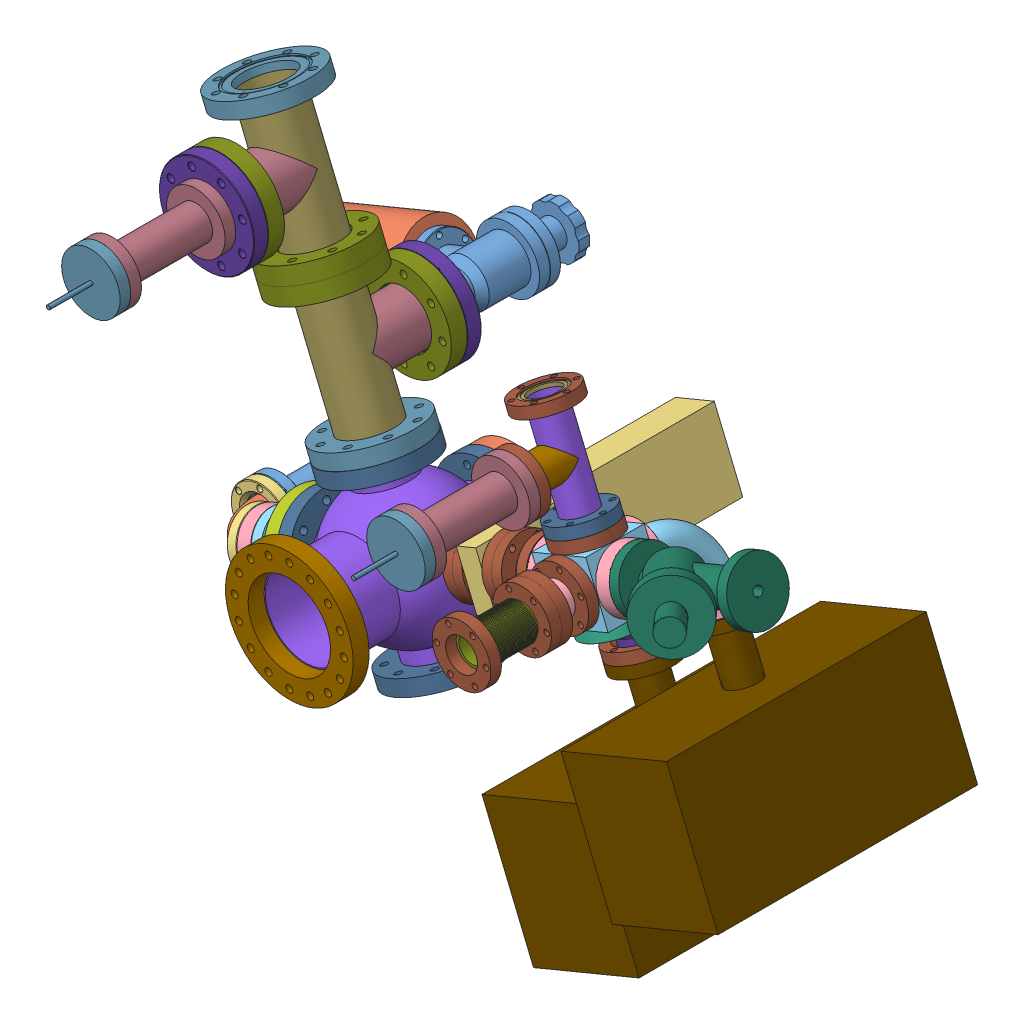
SolidWorks assembly Oven_BEC5_v3, configuration Default. Lengths in mm.
Overall size (747.25 839.97 656.21).
101 component instances, 42 part files, 80 mates.
Components (placement in the parent):
- mdc 275 halfnipple-1: mdc 275 halfnipple [Default] at (-24.8274 -18.3346 25.5574) size (69.34 69.34 62.48)
- L275-403502-6: L275-403502 [Default] at (27.1869 1.5159 24.2874) x (-0.923728 -0.383049 0) z (0 0 -1) size (77.27 39.99 77.27)
- 915002-3: 915002 [Default] at (-24.8274 -18.3346 38.2574) x (0 0 -1) z (1 0 0) size (12.7 69.34 69.34)
- mdc 2.75 doublesided_hole-1: mdc 2.75 doublesided_hole [Default] at (43.4775 8.648 79.5644) x (0.146727 -0.353833 -0.923728) z (0.923728 0.383049 0) size (69.34 69.34 19.05)
- 915002-4: 915002 [Default] at (14.1491 -3.5138 79.5644) x (0.923728 0.383049 0) z (0 0 1) size (12.7 69.34 69.34)
- 100014 (2.75 X 1.5 REC)-1: 100014 (2.75 X 1.5 REC) [Default] at (43.4775 8.648 79.5644) x (0.923728 0.383049 0) z (0 0 1) size (12.7 69.34 69.34)
- red1-402032-001-1: red1-402032-001 [Default] at (97.817 31.1814 79.5644) x (-0.923728 -0.383049 0) z (0 0 1) size (60.1 63.5 63.5)
- 110021 (4.5 X 2.5 NR)-1: 110021 (4.5 X 2.5 NR) [Default] at (97.817 31.1814 79.5644) x (-0.923728 -0.383049 0) z (0 0 1) size (17.27 113.54 113.54)
- custom_sixway_cross-1: custom_sixway_cross [Default] at (189.7246 79.077 65.1716) x (-0.923728 -0.383049 0) z (-0.383049 0.923728 0) size (201.17 247.4 209.3)
  - custom_sixway_tube-1: custom_sixway_tube [Default] at (-1.4041 14.3928 -9.0374) size (170.94 210.82 174.24)
  - 6in_CF_flange-3: 6in_CF_flange [Default] at (-1.4041 157.1408 -9.0374) x (1 0 0) z (0 -1 0) size (152.4 152.4 19.05)
  - 4.5in_CF_flange-1: 4.5in_CF_flange [Default] at (85.7179 14.3928 -9.0374) x (0 -1 0) z (0 0 1) size (114.3 17.53 114.3)
  - 4.5in_CF_flange-2: 4.5in_CF_flange [Default] at (-1.4041 14.3928 78.0846) x (1 0 0) z (0 -1 0) size (114.3 17.53 114.3)
  - 4.5in_CF_flange-3: 4.5in_CF_flange [Default] at (-1.4041 14.3928 -113.6854) x (1 0 0) z (0 -1 0) size (114.3 17.53 114.3)
  - 2.75in_CF_flange-1: 2.75in_CF_flange [Default] at (-97.9241 14.3928 -9.0374) x (0 -1 0) z (0 0 1) size (69.85 12.7 69.85)
  - 4.5in_CF_flange-4: 4.5in_CF_flange [Default] at (-1.4041 -90.2552 -9.0374) size (114.3 17.53 114.3)
- T4-404038-2: T4-404038 [Default] at (85.0757 335.1047 79.5644) x (-0.923728 -0.383049 0) z (-0.383049 0.923728 0) size (113.54 142.49 171.45)
  - 404038-001-1: 404038-001 [Default] at origin size (63.51 63.51 152.4)
  - 404038-002-1: 404038-002 [Default] at (0 0 76.2) x (1 0 0) z (0 1 0) size (63.5 63.5 78.71)
  - 110021 (4.5 X 2.5 NR)_1-1: 110021 (4.5 X 2.5 NR)_1 [Default] at (0 0 161.925) x (0 0 -1) z (1 0 0) size (17.27 113.54 113.54)
  - 100021 (4.5 X 2.5 R)_1-1: 100021 (4.5 X 2.5 R)_1 [Default] at (0 73.025 76.2) x (0 1 0) z (0 0 1) size (19.05 113.54 113.54)
    - 100021 (4.5 X 2.5 INS)_1-1: 100021 (4.5 X 2.5 INS)_1 [Default] at origin size (12.04 82.3 82.3)
    - 100021 (4.5 X 2.5 REC)_1-1: 100021 (4.5 X 2.5 REC)_1 [Default] at (-6.35 0 0) x (1 0 0) z (0 0 -1) size (19.05 113.54 113.54)
  - 100021 (4.5 X 2.5 R)_1-2: 100021 (4.5 X 2.5 R)_1 [Default] at (0 0 3.175) x (0 0 -1) z (1 0 0) size (19.05 113.54 113.54)
    - 100021 (4.5 X 2.5 INS)_1-1: 100021 (4.5 X 2.5 INS)_1 [Default] at origin size (12.04 82.3 82.3)
    - 100021 (4.5 X 2.5 REC)_1-1: 100021 (4.5 X 2.5 REC)_1 [Default] at (-6.35 0 0) x (1 0 0) z (0 0 -1) size (19.05 113.54 113.54)
- zerolength 2.75 to 4.5 mdc-3: zerolength 2.75 to 4.5 mdc [Default] at (55.8874 405.4928 165.2894) x (-0.923728 -0.383049 0) z (0 0 -1) size (113.54 113.54 17.27)
- L4-403004_1-3: L4-403004_1 [Default] at (231.0174 -16.8357 -129.9856) x (0 0 1) z (-0.923728 -0.383049 0) size (161.67 161.67 113.54)
  - 403004-001_1-1: 403004-001_1 [Default] at origin size (128.92 128.92 67.08)
  - 100021 (4.5 X 2.5 R)_2-1: 100021 (4.5 X 2.5 R)_2 [Default] at (92.202 95.377 0) x (1 0 0) z (0 0 -1) size (19.05 113.54 113.54)
    - 100021 (4.5 X 2.5 INS)_2-1: 100021 (4.5 X 2.5 INS)_2 [Default] at origin size (12.04 82.3 82.3)
    - 100021 (4.5 X 2.5 REC)_2-1: 100021 (4.5 X 2.5 REC)_2 [Default] at (-6.35 0 0) x (1 0 0) z (0 0 -1) size (19.05 113.54 113.54)
  - 100021 (4.5 X 2.5 R)_2-2: 100021 (4.5 X 2.5 R)_2 [Default] at (0 3.175 0) x (0 -1 0) z (0 0 -1) size (19.05 113.54 113.54)
    - 100021 (4.5 X 2.5 INS)_2-1: 100021 (4.5 X 2.5 INS)_2 [Default] at origin size (12.04 82.3 82.3)
    - 100021 (4.5 X 2.5 REC)_2-1: 100021 (4.5 X 2.5 REC)_2 [Default] at (-6.35 0 0) x (1 0 0) z (0 0 -1) size (19.05 113.54 113.54)
- gatevalve-1: gatevalve [Default] at (298.9549 11.514 55.3656) x (0.383049 -0.923728 0) z (0.923728 0.383049 0) size (88.9 280.54 50.84)
  - gatevalve_body-1: gatevalve_body [Default] at (-95.213 2.8522 48.3049) size (88.9 277.88 50.04)
  - 2.75in_CF_flange-3: 2.75in_CF_flange [Default] at (-95.213 -24.1988 73.7492) x (1 0 0) z (0 1 0) size (69.85 12.7 69.85)
  - 2.75in_CF_flange-4: 2.75in_CF_flange [Default] at (-95.213 -24.1988 35.6049) x (-1 0 0) z (0 -1 0) size (69.85 12.7 69.85)
- minilength_nipple-1: minilength_nipple [Default] at (349.6703 127.2966 78.7528) x (0.383049 -0.923728 0) z (0 0 1) size (69.85 44.45 69.85)
  - minilength_nipple_tube-1: minilength_nipple_tube [Default] at (-7.6879 4.7765 0.8117) size (38.1 19.05 38.1)
  - 2.75in_CF_flange-3: 2.75in_CF_flange [Default] at (-7.6879 14.3015 0.8117) size (69.85 12.7 69.85)
  - 2.75in_CF_flange-4: 2.75in_CF_flange [Default] at (-7.6879 -17.4485 0.8117) size (69.85 12.7 69.85)
- mdc 2.75 doublesided_hole-4: mdc 2.75 doublesided_hole [Default] at (371.6676 144.741 79.5644) x (0.146727 -0.353833 0.923728) z (-0.923728 -0.383049 0) size (69.34 69.34 19.05)
- mdc 2.75 doublesided_hole-5: mdc 2.75 doublesided_hole [Default] at (453.787 178.7941 79.5644) x (0.146727 -0.353833 0.923728) z (-0.923728 -0.383049 0) size (69.34 69.34 19.05)
- six way cube-1: six way cube [Default] at (421.5258 165.4161 79.5644) x (0 0 1) z (-0.923728 -0.383049 0) size (69.85 69.85 69.85)
- 2.75in  window mdc-1: 2.75in  window mdc [Default] at (439.7685 121.4235 79.5644) x (0.853273 0.353833 0.383049) z (-0.383049 0.923728 0) size (69.34 69.34 12.7)
  - Part3^2.75in  window mdc-1: Part3^2.75in  window mdc [Default] at origin size (69.34 69.34 12.7) (virtual)
  - Part4^2.75in  window mdc-1: Part4^2.75in  window mdc [Default] at (0 0 12.7) size (38.1 38.1 2.67) (virtual)
- T275-404002_a-1: T275-404002_a [Default] at (357.4671 319.8944 79.5644) x (0.923728 0.383049 0) z (0.383049 -0.923728 0) size (69.34 97.13 124.92)
  - 404002-001-1: 404002-001 [Default] at origin size (38.1 38.1 114.3)
  - 404002-002-1: 404002-002 [Default] at (0 0 57.15) x (-1 0 0) z (0 1 0) size (38.1 38.1 58.53)
  - 110014 (2.75 X 1.5 NR)_1-1: 110014 (2.75 X 1.5 NR)_1 [Default] at (0 0 113.2586) x (0 0 1) z (-1 0 0) size (12.7 69.34 69.34)
  - 100014 (2.75 X 1.5 R)-1: 100014 (2.75 X 1.5 R) [Default] at (0 62.4586 57.15) x (0 -1 0) z (1 0 0) size (12.7 69.34 69.34)
    - 100014 (2.75 X 1.5 REC)_1-1: 100014 (2.75 X 1.5 REC)_1 [Default] at origin size (12.7 69.34 69.34)
    - 100014 (2.75 X 1.5 INS)-1: 100014 (2.75 X 1.5 INS) [Default] at (1.17 0 0) x (1 0 0) z (0 0.994423 -0.105464) size (6.96 48.1 48.1)
  - 100014 (2.75 X 1.5 R)-2: 100014 (2.75 X 1.5 R) [Default] at (0 0 -5.3086) x (0 0 1) z (-1 0 0) size (12.7 69.34 69.34)
    - 100014 (2.75 X 1.5 REC)_1-1: 100014 (2.75 X 1.5 REC)_1 [Default] at origin size (12.7 69.34 69.34)
    - 100014 (2.75 X 1.5 INS)-1: 100014 (2.75 X 1.5 INS) [Default] at (1.17 0 0) x (1 0 0) z (0 0.994423 -0.105464) size (6.96 48.1 48.1)
- 2.75in_CF_flange-1: 2.75in_CF_flange [Default] at (403.2831 209.4086 79.5644) x (-0.923728 -0.383049 0) z (0 0 1) size (69.85 12.7 69.85)
- nipple 2.75 mdc-2: nipple 2.75 mdc [Default] at (379.3584 267.1034 142.023) x (1 0 0) z (0 -1 0) size (69.85 125.22 69.85)
- ion gauge uhv 24p footprint-2: ion gauge uhv 24p footprint [Default] at (379.3584 267.1034 279.945) x (1 0 0) z (0 1 0) size (69.85 147.62 69.85)
- valve mdc inline all metal small-1: valve mdc inline all metal small [Default] at (470.2109 185.6047 79.5644) x (-0.383049 0.923728 0) z (0 0 -1) size (75.44 172.37 161.4)
- minilength_nipple-2: minilength_nipple [Default] at (429.2137 166.2277 131.9379) x (1 0 0) z (0 -1 0) size (69.85 44.45 69.85)
  - minilength_nipple_tube-1: minilength_nipple_tube [Default] at (-7.6879 4.7765 0.8117) size (38.1 19.05 38.1)
  - 2.75in_CF_flange-3: 2.75in_CF_flange [Default] at (-7.6879 14.3015 0.8117) size (69.85 12.7 69.85)
  - 2.75in_CF_flange-4: 2.75in_CF_flange [Default] at (-7.6879 -17.4485 0.8117) size (69.85 12.7 69.85)
- Bellow_2.75in_CF-1: Bellow_2.75in_CF [Default] at (449.3378 155.3944 206.3015) x (1 0 0) z (0 1 0) size (96.68 84.96 96.68)
  - 2.75in_bellow_tube-1: 2.75in_bellow_tube [Default] at (-27.8121 6.8508 10.0217) size (43.18 63.5 43.18)
  - 2.75in_CF_flange-1: 2.75in_CF_flange [Default] at (-27.8121 47.3621 10.0217) x (-0.837169 0 -0.546944) z (-0.546944 0 0.837169) size (69.85 12.7 69.85)
  - 2.75in_CF_flange-2: 2.75in_CF_flange [Default] at (-27.8121 -24.8992 10.0217) x (-0.837169 0 -0.546944) z (-0.546944 0 0.837169) size (69.85 12.7 69.85)
- 404002-001_1-1: 404002-001_1 [Default] at (115.1337 -161.6135 43.2434)
- 402032-2: 402032 [Default] at (238.3145 -34.4327 -129.9856) x (0.383049 -0.923728 0) z (0 0 1) size (74.93 113.54 113.54)
  - 402032-001-1: 402032-001 [Default] at origin size (60.1 63.5 63.5)
  - 110021 (4.5 X 2.5 NR)-1: 110021 (4.5 X 2.5 NR) [Default] at (-9.525 0 0) size (17.27 113.54 113.54)
  - 100014 (2.75 X 1.5 R)-1: 100014 (2.75 X 1.5 R) [Default] at (65.405 0 0) x (-1 0 0) z (0 0 -1) size (12.7 69.34 69.34)
    - 100014 (2.75 X 1.5 REC)_1-1: 100014 (2.75 X 1.5 REC)_1 [Default] at origin size (12.7 69.34 69.34)
    - 100014 (2.75 X 1.5 INS)-1: 100014 (2.75 X 1.5 INS) [Default] at (1.17 0 0) x (1 0 0) z (0 0.994423 -0.105464) size (6.96 48.1 48.1)
- Ion_Pump_40ls-1: Ion_Pump_40ls [Default] at (307.7138 -325.5851 -18.3452) x (0 0 -1) z (-0.383049 0.923728 0) size (309.88 136.4 230.12)
- Ion_Pump_40ls-2: Ion_Pump_40ls [Default] at (584.1153 -102.8759 -146.9855) x (0 0 1) z (-0.383049 0.923728 0) size (309.88 136.4 230.12)
- T4-404038-3: T4-404038 [Default] at (92.3728 317.5077 79.5644) x (-0.923728 -0.383049 0) z (0.383049 -0.923728 0) size (113.54 142.49 171.45)
  - 404038-001-1: 404038-001 [Default] at origin size (63.51 63.51 152.4)
  - 404038-002-1: 404038-002 [Default] at (0 0 76.2) x (1 0 0) z (0 1 0) size (63.5 63.5 78.71)
  - 110021 (4.5 X 2.5 NR)_1-1: 110021 (4.5 X 2.5 NR)_1 [Default] at (0 0 161.925) x (0 0 -1) z (1 0 0) size (17.27 113.54 113.54)
  - 100021 (4.5 X 2.5 R)_1-1: 100021 (4.5 X 2.5 R)_1 [Default] at (0 73.025 76.2) x (0 1 0) z (0 0 1) size (19.05 113.54 113.54)
    - 100021 (4.5 X 2.5 INS)_1-1: 100021 (4.5 X 2.5 INS)_1 [Default] at origin size (12.04 82.3 82.3)
    - 100021 (4.5 X 2.5 REC)_1-1: 100021 (4.5 X 2.5 REC)_1 [Default] at (-6.35 0 0) x (1 0 0) z (0 0 -1) size (19.05 113.54 113.54)
  - 100021 (4.5 X 2.5 R)_1-2: 100021 (4.5 X 2.5 R)_1 [Default] at (0 0 3.175) x (0 0 -1) z (1 0 0) size (19.05 113.54 113.54)
    - 100021 (4.5 X 2.5 INS)_1-1: 100021 (4.5 X 2.5 INS)_1 [Default] at origin size (12.04 82.3 82.3)
    - 100021 (4.5 X 2.5 REC)_1-1: 100021 (4.5 X 2.5 REC)_1 [Default] at (-6.35 0 0) x (1 0 0) z (0 0 -1) size (19.05 113.54 113.54)
- nipple 2.75 mdc-3: nipple 2.75 mdc [Default] at (55.8874 405.4928 307.7834) x (1 0 0) z (0 1 0) size (69.85 125.22 69.85)
- ion gauge uhv 24p footprint-3: ion gauge uhv 24p footprint [Default] at (55.8874 405.4928 320.4834) x (1 0 0) z (0 1 0) size (69.85 147.62 69.85)
- zerolength 2.75 to 4.5 mdc-4: zerolength 2.75 to 4.5 mdc [Default] at (121.5611 247.1196 -6.1606) size (113.54 113.54 17.27)
- angle valve 1.5 inch 310029 mdc-3: angle valve 1.5 inch 310029 mdc [Default] at (121.5611 247.1196 -124.1436) x (-0.923728 -0.383049 0) z (0.383049 -0.923728 0) size (100.2 160.92 75.44)
- turbo pump footpring-2: turbo pump footpring [Default] at (63.8429 223.1852 -86.8564) x (-0.383049 0.923728 0) z (0 0 1) size (91.44 162.05 91.44)
- L_275-1: L_275 [Default] at (450.1304 96.4358 -35.3452) x (0 0 1) z (-0.923728 -0.383049 0) size (127.35 127.35 94.72)
  - 910014 (2.75 ROTA INSERT)-1: 910014 (2.75 ROTA INSERT) [Default] at (0 2.3114 0) x (-0.343989 0 0.938974) z (0 -1 0) size (48.06 48.06 6.96)
  - 915002 (2.75 ROTA FLANGE)-1: 915002 (2.75 ROTA FLANGE) [Default] at (79.9846 74.676 0) x (0 0.5 -0.866025) z (1 0 0) size (69.34 69.34 12.7)
  - 915002 (2.75 ROTA FLANGE)-2: 915002 (2.75 ROTA FLANGE) [Default] at (0 -5.3086 0) x (0.5 0 -0.866025) z (0 -1 0) size (69.34 69.34 12.7)
  - 042207-1: 042207 [Default] at origin size (93.73 93.73 38.1)
  - 910014 (2.75 ROTA INSERT)-2: 910014 (2.75 ROTA INSERT) [Default] at (72.3646 74.676 0) x (0 0.872746 -0.488175) z (1 0 0) size (48.06 48.06 6.96)
Mates (geometry in assembly coordinates):
- Coincident9: coincident anti-aligned: plane of mdc 275 halfnipple-1 through (-24.8274 -18.3346 24.2874) normal (0 0 1); plane of L275-403502-6 through (-25.6042 -20.3753 24.2874) normal (0 0 -1)
- Tangent4: tangent: cylinder of mdc 275 halfnipple-1 through (-24.8274 -18.3346 24.2874) axis (0 0 -1) radius 17.4625; face of L275-403502-6
- Coincident12: coincident anti-aligned: plane of mdc 275 halfnipple-1 through (-24.8274 -18.3346 25.5574) normal (0 0 1); plane of 915002-3 through (-24.8274 -18.3346 25.5574) normal (0 0 -1)
- Coincident14: coincident anti-aligned: plane of mdc 275 halfnipple-1 through (-24.8274 -18.3346 25.5574) normal (0 0 1); plane of 915002-3 through (-24.8274 -18.3346 25.5574) normal (0 0 -1)
- Coincident15: coincident aligned: circle of mdc 275 halfnipple-1; circle of 915002-3
- Coincident16: coincident anti-aligned: plane of L275-403502-6 through (27.1869 1.5159 81.4374) normal (0.923728 0.383049 0); plane of mdc 2.75 doublesided_hole-1 through (27.0536 1.8374 79.5644) normal (-0.923728 -0.383049 0)
- Tangent6: tangent: face of L275-403502-6; cylinder of mdc 2.75 doublesided_hole-1 through (27.6508 2.0851 79.5644) axis (0.923728 0.383049 0) radius 20.955
- Coincident17: coincident anti-aligned: plane of mdc 2.75 doublesided_hole-1 through (25.8804 1.3509 79.5644) normal (-0.923728 -0.383049 0); plane of 915002-4 through (25.8804 1.3509 79.5644) normal (0.923728 0.383049 0)
- Coincident18: coincident anti-aligned: circle of 915002-4; circle of mdc 2.75 doublesided_hole-1
- Coincident19: coincident anti-aligned: plane of mdc 2.75 doublesided_hole-1 through (42.3043 8.1616 79.5644) normal (0.923728 0.383049 0); plane of red1-402032-001-1 through (49.2852 -8.6729 79.5644) normal (-0.923728 -0.383049 0)
- Concentric1: concentric anti-aligned: cylinder of mdc 2.75 doublesided_hole-1 through (41.7071 7.9139 79.5644) axis (0.923728 0.383049 0) radius 20.955; cylinder of red1-402032-001-1 through (48.17 10.5939 79.5644) axis (-0.923728 -0.383049 0) radius 19.05
- Coincident20: coincident anti-aligned: plane of mdc 2.75 doublesided_hole-1 through (43.4775 8.648 79.5644) normal (0.923728 0.383049 0); plane of 100014 (2.75 X 1.5 REC)-1 through (32.2261 35.7809 79.5644) normal (-0.923728 -0.383049 0)
- Concentric2: concentric anti-aligned: cylinder of 100014 (2.75 X 1.5 REC)-1 through (46.9969 10.1074 79.5644) axis (0.923728 0.383049 0) radius 24.0754; cylinder of red1-402032-001-1 through (48.17 10.5939 79.5644) axis (-0.923728 -0.383049 0) radius 19.05
- Coincident22: coincident anti-aligned: plane of red1-402032-001-1 through (109.6626 2.6156 79.5644) normal (0.923728 0.383049 0); plane of custom_sixway_cross-1/4.5in_CF_flange-1 through (97.817 31.1814 79.5644) normal (-0.923728 -0.383049 0)
- Coincident23: coincident aligned: circle of red1-402032-001-1; circle of custom_sixway_cross-1/4.5in_CF_flange-1
- Coincident24: coincident anti-aligned: plane of 110021 (4.5 X 2.5 NR)-1 through (116.5949 -14.1016 79.5644) normal (0.923728 0.383049 0); plane of custom_sixway_cross-1/4.5in_CF_flange-1 through (97.817 31.1814 79.5644) normal (-0.923728 -0.383049 0)
- Concentric3: concentric aligned: cylinder of red1-402032-001-1 through (93.4178 29.3571 79.5644) axis (-0.923728 -0.383049 0) radius 31.75; cylinder of 110021 (4.5 X 2.5 NR)-1 through (92.8774 29.1331 79.5644) axis (-0.923728 -0.383049 0) radius 30.1625
- Parallel6: parallel aligned: plane of mdc 275 halfnipple-1 through (-24.8274 -18.3346 -36.9266) normal (0 0 -1); plane of custom_sixway_cross-1/4.5in_CF_flange-4 through (194.4833 71.2667 -25.0836) normal (0 0 -1)
- Coincident33: coincident anti-aligned: plane of T4-404038-3/100021 (4.5 X 2.5 R)_1-2/100021 (4.5 X 2.5 REC)_1-1 through (88.7243 326.3062 128.5864) normal (-0.383049 0.923728 0); plane of T4-404038-2/100021 (4.5 X 2.5 R)_1-2/100021 (4.5 X 2.5 REC)_1-1 through (88.7243 326.3062 30.5424) normal (0.383049 -0.923728 0)
- Concentric9: concentric aligned: circle of custom_sixway_cross-1/4.5in_CF_flange-3; circle of T4-404038-2/100021 (4.5 X 2.5 R)_1-2/100021 (4.5 X 2.5 INS)_1-1
- Parallel8: parallel aligned: plane of custom_sixway_cross-1/6in_CF_flange-3 through (194.4833 71.2667 222.3124) normal (0 0 1); plane of T4-404038-2/100021 (4.5 X 2.5 R)_1-1/100021 (4.5 X 2.5 REC)_1-1 through (10.6044 386.7149 165.2894) normal (0 0 1)
- Coincident35: coincident anti-aligned: plane of T4-404038-2/100021 (4.5 X 2.5 R)_1-1/100021 (4.5 X 2.5 REC)_1-1 through (10.6044 386.7149 165.2894) normal (0 0 1); plane of zerolength 2.75 to 4.5 mdc-3 through (55.8874 405.4928 165.2894) normal (0 0 -1)
- Concentric10: concentric aligned: circle of T4-404038-2/100021 (4.5 X 2.5 R)_1-1/100021 (4.5 X 2.5 INS)_1-1; circle of zerolength 2.75 to 4.5 mdc-3
- Coincident43: coincident anti-aligned: plane of custom_sixway_cross-1/4.5in_CF_flange-4 through (194.4833 71.2667 -25.0836) normal (0 0 -1); plane of L4-403004_1-3/100021 (4.5 X 2.5 R)_2-1/100021 (4.5 X 2.5 REC)_2-1 through (175.7055 116.5497 -25.0836) normal (0 0 1)
- Concentric14: concentric anti-aligned: circle of custom_sixway_cross-1/4.5in_CF_flange-4; circle of L4-403004_1-3/100021 (4.5 X 2.5 R)_2-1/100021 (4.5 X 2.5 INS)_2-1
- Parallel11: parallel anti-aligned: plane of T4-404038-2/110021 (4.5 X 2.5 NR)_1-1 through (23.0505 484.6794 128.5864) normal (-0.383049 0.923728 0); plane of L4-403004_1-3/100021 (4.5 X 2.5 R)_2-2/100021 (4.5 X 2.5 REC)_2-1 through (234.6659 -25.6342 -80.9636) normal (0.383049 -0.923728 0)
- Coincident48: coincident anti-aligned: plane of custom_sixway_cross-1/2.75in_CF_flange-1 through (283.6416 108.2386 79.5644) normal (0.923728 0.383049 0); plane of gatevalve-1/2.75in_CF_flange-4 through (283.6416 108.2386 79.5644) normal (-0.923728 -0.383049 0)
- Coincident49: coincident aligned: circle of custom_sixway_cross-1/2.75in_CF_flange-1; circle of gatevalve-1/2.75in_CF_flange-4
- Coincident51: coincident anti-aligned: plane of gatevalve-1/2.75in_CF_flange-3 through (330.6079 127.7145 79.5644) normal (0.923728 0.383049 0); plane of minilength_nipple-1/2.75in_CF_flange-4 through (330.6079 127.7145 79.5644) normal (-0.923728 -0.383049 0)
- Coincident52: coincident anti-aligned: circle of gatevalve-1/2.75in_CF_flange-3; circle of minilength_nipple-1/2.75in_CF_flange-4
- Coincident53: coincident anti-aligned: plane of minilength_nipple-1/2.75in_CF_flange-3 through (371.6676 144.741 79.5644) normal (0.923728 0.383049 0); plane of mdc 2.75 doublesided_hole-4 through (371.6676 144.741 79.5644) normal (-0.923728 -0.383049 0)
- Concentric17: concentric aligned: circle of minilength_nipple-1/2.75in_CF_flange-3; circle of mdc 2.75 doublesided_hole-4
- Coincident54: coincident anti-aligned: plane of mdc 2.75 doublesided_hole-4 through (389.2646 152.0381 79.5644) normal (0.923728 0.383049 0); plane of six way cube-1 through (375.8866 184.2993 44.6394) normal (-0.923728 -0.383049 0)
- Concentric18: concentric anti-aligned: circle of mdc 2.75 doublesided_hole-4; circle of six way cube-1
- Parallel14: parallel aligned: plane of custom_sixway_cross-1/6in_CF_flange-3 through (194.4833 71.2667 222.3124) normal (0 0 1); plane of six way cube-1 through (402.6426 119.7769 114.4894) normal (0 0 1)
- Coincident56: coincident anti-aligned: plane of mdc 2.75 doublesided_hole-5 through (453.787 178.7941 79.5644) normal (-0.923728 -0.383049 0); plane of six way cube-1 through (440.409 211.0553 44.6394) normal (0.923728 0.383049 0)
- Coincident57: coincident aligned: circle of mdc 2.75 doublesided_hole-5; circle of six way cube-1
- Coincident58: coincident anti-aligned: plane of six way cube-1 through (402.6426 119.7769 44.6394) normal (0.383049 -0.923728 0); plane of 2.75in  window mdc-1/Part3^2.75in  window mdc-1 through (434.9038 133.1549 79.5644) normal (-0.383049 0.923728 0)
- Concentric19: concentric aligned: circle of six way cube-1; circle of 2.75in  window mdc-1/Part3^2.75in  window mdc-1
- Coincident59: coincident anti-aligned: plane of six way cube-1 through (375.8866 184.2993 44.6394) normal (-0.383049 0.923728 0); plane of 2.75in_CF_flange-1 through (408.1478 197.6773 79.5644) normal (0.383049 -0.923728 0)
- Concentric20: concentric anti-aligned: circle of six way cube-1; circle of 2.75in_CF_flange-1
- Coincident60: coincident anti-aligned: plane of T275-404002_a-1/110014 (2.75 X 1.5 NR)_1-1 through (403.2831 209.4086 50.1539) normal (0.383049 -0.923728 0); plane of 2.75in_CF_flange-1 through (403.2831 209.4086 79.5644) normal (-0.383049 0.923728 0)
- Concentric21: concentric anti-aligned: circle of T275-404002_a-1/110014 (2.75 X 1.5 NR)_1-1; circle of 2.75in_CF_flange-1
- Parallel15: parallel: plane of six way cube-1 through (402.6426 119.7769 114.4894) normal (0 0 1); plane of T275-404002_a-1/100014 (2.75 X 1.5 R)-1/100014 (2.75 X 1.5 REC)_1-1 through (368.107 294.2362 142.023) normal (0 0 1)
- Coincident62: coincident: plane of T275-404002_a-1/100014 (2.75 X 1.5 R)-1/100014 (2.75 X 1.5 REC)_1-1 through (368.107 294.2362 142.023) normal (0 0 1); plane of nipple 2.75 mdc-2 through (379.3584 267.1034 142.023) normal (0 0 -1)
- Concentric22: concentric: circle of T275-404002_a-1/100014 (2.75 X 1.5 R)-1/100014 (2.75 X 1.5 REC)_1-1; circle of nipple 2.75 mdc-2
- Coincident63: coincident anti-aligned: plane of nipple 2.75 mdc-2 through (379.3584 267.1034 267.245) normal (0 0 1); plane of ion gauge uhv 24p footprint-2 through (379.3584 267.1034 267.245) normal (0 0 -1)
- Concentric23: concentric anti-aligned: cylinder of nipple 2.75 mdc-2 through (379.3584 267.1034 267.245) axis (0 0 -1) radius 17.526; cylinder of ion gauge uhv 24p footprint-2 through (379.3584 267.1034 183.1202) axis (0 0 1) radius 16.637
- Coincident65: coincident anti-aligned: plane of mdc 2.75 doublesided_hole-5 through (470.2109 185.6047 79.5644) normal (0.923728 0.383049 0); plane of valve mdc inline all metal small-1 through (470.2109 185.6047 79.5644) normal (-0.923728 -0.383049 0)
- Concentric25: concentric aligned: circle of mdc 2.75 doublesided_hole-5; circle of valve mdc inline all metal small-1
- Angle1: planar angle = 0.785398 rad aligned: plane of valve mdc inline all metal small-1 through (593.8073 236.8573 167.8974) normal (0.653174 0.270857 0.707107); plane of nipple 2.75 mdc-2 through (379.3584 267.1034 154.723) normal (0 0 1)
- Coincident72: coincident anti-aligned: plane of six way cube-1 through (402.6426 119.7769 114.4894) normal (0 0 1); plane of minilength_nipple-2/2.75in_CF_flange-4 through (421.5258 165.4161 114.4894) normal (0 0 -1)
- Concentric29: concentric aligned: circle of six way cube-1; circle of minilength_nipple-2/2.75in_CF_flange-4
- Coincident74: coincident anti-aligned: plane of minilength_nipple-2/2.75in_CF_flange-3 through (421.5258 165.4161 158.9394) normal (0 0 1); plane of Bellow_2.75in_CF-1/2.75in_CF_flange-1 through (421.5258 165.4161 158.9394) normal (0 0 -1)
- Coincident75: coincident aligned: circle of minilength_nipple-2/2.75in_CF_flange-3; circle of Bellow_2.75in_CF-1/2.75in_CF_flange-1
- Coincident77: coincident anti-aligned: plane of L4-403004_1-3/100021 (4.5 X 2.5 R)_2-2/100021 (4.5 X 2.5 REC)_2-1 through (234.6659 -25.6342 -80.9636) normal (0.383049 -0.923728 0); plane of 402032-2/110021 (4.5 X 2.5 NR)-1 through (279.9489 -6.8564 -129.9856) normal (-0.383049 0.923728 0)
- Concentric30: concentric anti-aligned: circle of L4-403004_1-3/100021 (4.5 X 2.5 R)_2-2/100021 (4.5 X 2.5 INS)_2-1; circle of 402032-2/110021 (4.5 X 2.5 NR)-1
- Coincident82: coincident anti-aligned: plane of 402032-2/100014 (2.75 X 1.5 R)-1/100014 (2.75 X 1.5 REC)_1-1 through (290.5007 -83.5977 -129.9856) normal (0.383049 -0.923728 0); plane of Ion_Pump_40ls-1 through (263.3678 -94.8491 -129.9856) normal (-0.383049 0.923728 0)
- Concentric31: concentric aligned: circle of 402032-2/100014 (2.75 X 1.5 R)-1/100014 (2.75 X 1.5 REC)_1-1; circle of Ion_Pump_40ls-1
- Parallel19: parallel aligned: plane of custom_sixway_cross-1/6in_CF_flange-3 through (194.4833 71.2667 222.3124) normal (0 0 1); plane of Ion_Pump_40ls-1 through (227.0292 -185.2605 24.9544) normal (0 0 1)
- Parallel20: parallel aligned: plane of Bellow_2.75in_CF-1/2.75in_CF_flange-2 through (421.5258 165.4161 243.9007) normal (0 0 1); plane of Ion_Pump_40ls-2 through (541.8198 53.3678 119.5948) normal (0 0 1)
- Coincident92: coincident anti-aligned: plane of custom_sixway_cross-1/4.5in_CF_flange-2 through (154.398 167.933 79.5644) normal (-0.383049 0.923728 0); plane of T4-404038-3/110021 (4.5 X 2.5 NR)_1-1 through (154.398 167.933 30.5424) normal (0.383049 -0.923728 0)
- Concentric34: concentric aligned: circle of custom_sixway_cross-1/4.5in_CF_flange-2; circle of T4-404038-3/110021 (4.5 X 2.5 NR)_1-1
- Parallel23: parallel anti-aligned: plane of custom_sixway_cross-1/6in_CF_flange-3 through (194.4833 71.2667 222.3124) normal (0 0 1); plane of T4-404038-3/100021 (4.5 X 2.5 R)_1-1/100021 (4.5 X 2.5 REC)_1-1 through (76.2782 228.3418 -6.1606) normal (0 0 -1)
- Coincident98: coincident anti-aligned: plane of zerolength 2.75 to 4.5 mdc-3 through (55.8874 405.4928 182.5614) normal (0 0 1); plane of nipple 2.75 mdc-3 through (55.8874 405.4928 182.5614) normal (0 0 -1)
- Concentric35: concentric anti-aligned: circle of zerolength 2.75 to 4.5 mdc-3; circle of nipple 2.75 mdc-3
- Coincident99: coincident anti-aligned: plane of nipple 2.75 mdc-3 through (55.8874 405.4928 307.7834) normal (0 0 1); plane of ion gauge uhv 24p footprint-3 through (55.8874 405.4928 307.7834) normal (0 0 -1)
- Concentric36: concentric aligned: circle of nipple 2.75 mdc-3; circle of ion gauge uhv 24p footprint-3
- Coincident100: coincident anti-aligned: plane of T4-404038-3/100021 (4.5 X 2.5 R)_1-1/100021 (4.5 X 2.5 REC)_1-1 through (76.2782 228.3418 -6.1606) normal (0 0 -1); plane of zerolength 2.75 to 4.5 mdc-4 through (121.5611 247.1196 -6.1606) normal (0 0 1)
- Concentric37: concentric aligned: circle of T4-404038-3/100021 (4.5 X 2.5 R)_1-1/100021 (4.5 X 2.5 INS)_1-1; circle of zerolength 2.75 to 4.5 mdc-4
- Coincident101: coincident anti-aligned: plane of zerolength 2.75 to 4.5 mdc-4 through (121.5611 247.1196 -23.4326) normal (0 0 -1); plane of angle valve 1.5 inch 310029 mdc-3 through (121.5611 247.1196 -23.4326) normal (0 0 1)
- Concentric38: concentric aligned: circle of zerolength 2.75 to 4.5 mdc-4; circle of angle valve 1.5 inch 310029 mdc-3
- Parallel24: parallel aligned: plane of custom_sixway_cross-1/2.75in_CF_flange-1 through (271.9102 103.3739 79.5644) normal (-0.923728 -0.383049 0); plane of angle valve 1.5 inch 310029 mdc-3 through (63.8429 223.1852 -86.8564) normal (-0.923728 -0.383049 0)
- Coincident106: coincident anti-aligned: plane of angle valve 1.5 inch 310029 mdc-3 through (63.8429 223.1852 -86.8564) normal (-0.923728 -0.383049 0); plane of turbo pump footpring-2 through (63.8429 223.1852 -86.8564) normal (0.923728 0.383049 0)
- Concentric40: concentric anti-aligned: circle of angle valve 1.5 inch 310029 mdc-3; circle of turbo pump footpring-2
- Coincident107: coincident anti-aligned: plane of six way cube-1 through (402.6426 119.7769 44.6394) normal (0 0 -1); plane of L_275-1/915002 (2.75 ROTA FLANGE)-1 through (421.5258 165.4161 44.6394) normal (0 0 1)
- Concentric41: concentric aligned: circle of six way cube-1; circle of L_275-1/910014 (2.75 ROTA INSERT)-2
- Parallel25: parallel aligned: plane of 2.75in  window mdc-1/Part3^2.75in  window mdc-1 through (439.7685 121.4235 79.5644) normal (0.383049 -0.923728 0); plane of L_275-1/915002 (2.75 ROTA FLANGE)-2 through (452.1638 91.5321 -35.3452) normal (0.383049 -0.923728 0)
- Coincident109: coincident anti-aligned: plane of Ion_Pump_40ls-2 through (452.1638 91.5321 -35.3452) normal (-0.383049 0.923728 0); plane of L_275-1/915002 (2.75 ROTA FLANGE)-2 through (452.1638 91.5321 -35.3452) normal (0.383049 -0.923728 0)
- Concentric42: concentric aligned: circle of Ion_Pump_40ls-2; circle of L_275-1/915002 (2.75 ROTA FLANGE)-2
